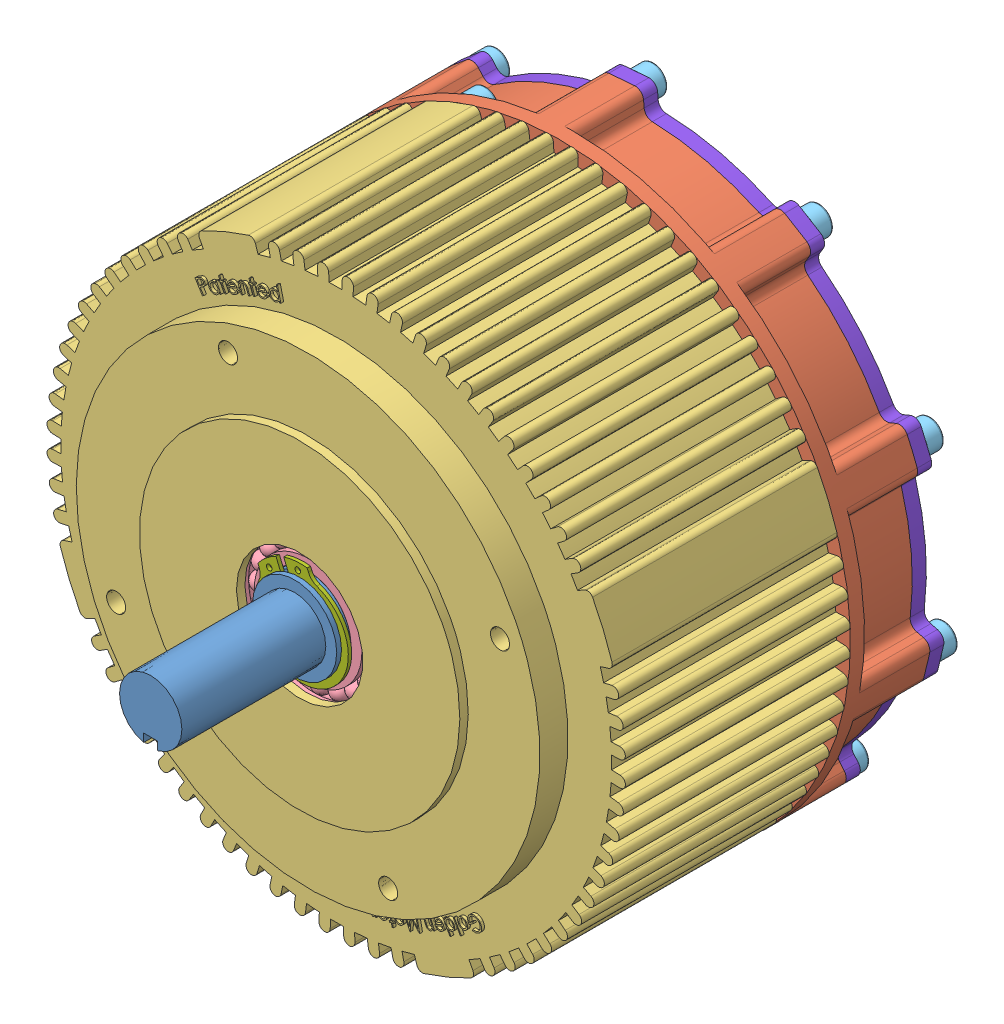
SolidWorks assembly (外形图）水冷图, configuration 默认. Lengths in mm.
Overall size (269.45 269.45 189).
25 component instances, 8 part files, 24 mates.
Components (placement in the parent):
- 普通轴-1: 普通轴 [默认] at (-1.1469 2.9597 -85) size (35 35 168.2)
- 水冷盖-1: 水冷盖 [默认] at (-1.1469 2.9597 -43.6) x (0 0 -1) z (0.922836 0.385193 0) size (49.2 206 206)
- 机壳-1: 机壳 [默认] at (-1.1469 2.9597 30.2) x (0.922836 0.385193 0) z (0 0 -1) size (206 206 93)
- Deep groove ball bearings GB-1: Deep groove ball bearings GB [Rolling bearings 16006 GB 276-94] at (-1.1469 2.9597 22.7) x (0 0 1) z (-0.99974 -0.022781 0) size (9 55 55)
- Hexagon socket head cap screws GB-2: Hexagon socket head cap screws GB [GB_FASTENER_SCREWS_HSHCS M6X16-N] at (-96.501 25.5783 -103.8) x (0 0 1) z (-1 0 0) size (22 10 10)
- Hexagon socket head cap screws GB-3: Hexagon socket head cap screws GB [GB_FASTENER_SCREWS_HSHCS M8X16-N] at (-64.9357 -2.2351 -105.8) x (0 0 1) z (-1 0 0) size (24 13 13)
- Hexagon socket head cap screws GB-4: Hexagon socket head cap screws GB [GB_FASTENER_SCREWS_HSHCS M4X12-N] at (31.032 -9.4809 7.2) x (0 0 1) z (-1 0 0) size (16 7 7)
- Hexagon socket head cap screws GB-8: Hexagon socket head cap screws GB [GB_FASTENER_SCREWS_HSHCS M6X16-N] at (-38.8958 93.3977 -73.8) x (0 0 1) z (-1 0 0) size (22 10 10)
- Hexagon socket head cap screws GB-9: Hexagon socket head cap screws GB [GB_FASTENER_SCREWS_HSHCS M6X16-N] at (36.602 -87.4782 -73.8) x (0 0 1) z (1 0 0) size (22 10 10)
- Deep groove ball bearings GB-2: Deep groove ball bearings GB [Rolling bearings 6304 GB 276-94] at (-1.1469 2.9597 -53.1) x (0 0 -1) z (0.923728 0.383049 0) size (15 52 52)
- Circlips for holes--Type A GB-1: Circlips for holes--Type A GB [GB_CONNECTING_PIECE_RING_RRH 52] at (-0.6872 1.8513 -62.8) x (0.923728 0.383049 0) z (0 0 -1) size (56.2 54.06 2)
- Circlips for shaft--Type B GB-1: Circlips for shaft--Type B GB [GB_CONNECTING_PIECE_RINGS_CSB 30] at (-0.7907 2.1007 28.8) x (0.923728 0.383049 0) z (0 0 -1) size (33.5 36.62 1.2)
- 水冷盖板-1: 水冷盖板 [默认] at (-1.1469 2.9597 -97.8) x (0.9967 0.081168 0) z (0 0 1) size (198.8 206 5)
- Hexagon socket head cap screws GB-19: Hexagon socket head cap screws GB [GB_FASTENER_SCREWS_HSHCS M6X16-N] at (-91.5848 -34.7892 -103.8) x (0 0 1) z (-0.809017 -0.587785 0) size (22 10 10)
- Hexagon socket head cap screws GB-20: Hexagon socket head cap screws GB [GB_FASTENER_SCREWS_HSHCS M6X16-N] at (-52.1244 -80.7379 -103.8) x (0 0 1) z (-0.309017 -0.951057 0) size (22 10 10)
- Hexagon socket head cap screws GB-21: Hexagon socket head cap screws GB [GB_FASTENER_SCREWS_HSHCS M6X16-N] at (6.8076 -94.7169 -103.8) x (0 0 1) z (0.309017 -0.951057 0) size (22 10 10)
- Hexagon socket head cap screws GB-22: Hexagon socket head cap screws GB [GB_FASTENER_SCREWS_HSHCS M6X16-N] at (62.7013 -71.3868 -103.8) x (0 0 1) z (0.809017 -0.587785 0) size (22 10 10)
- Hexagon socket head cap screws GB-23: Hexagon socket head cap screws GB [GB_FASTENER_SCREWS_HSHCS M6X16-N] at (94.2072 -19.6588 -103.8) x (0 0 1) z (1 0 0) size (22 10 10)
- Hexagon socket head cap screws GB-24: Hexagon socket head cap screws GB [GB_FASTENER_SCREWS_HSHCS M6X16-N] at (89.291 40.7087 -103.8) x (0 0 1) z (0.809017 0.587785 0) size (22 10 10)
- Hexagon socket head cap screws GB-25: Hexagon socket head cap screws GB [GB_FASTENER_SCREWS_HSHCS M6X16-N] at (49.8307 86.6573 -103.8) x (0 0 1) z (0.309017 0.951057 0) size (22 10 10)
- Hexagon socket head cap screws GB-26: Hexagon socket head cap screws GB [GB_FASTENER_SCREWS_HSHCS M6X16-N] at (-9.1014 100.6364 -103.8) x (0 0 1) z (-0.309017 0.951057 0) size (22 10 10)
- Hexagon socket head cap screws GB-27: Hexagon socket head cap screws GB [GB_FASTENER_SCREWS_HSHCS M6X16-N] at (-64.9951 77.3062 -103.8) x (0 0 1) z (-0.809017 0.587785 0) size (22 10 10)
- Hexagon socket head cap screws GB-28: Hexagon socket head cap screws GB [GB_FASTENER_SCREWS_HSHCS M8X16-N] at (4.0479 -60.8291 -105.8) x (0 0 1) z (0 -1 0) size (24 13 13)
- Hexagon socket head cap screws GB-29: Hexagon socket head cap screws GB [GB_FASTENER_SCREWS_HSHCS M8X16-N] at (62.6419 8.1545 -105.8) x (0 0 1) z (1 0 0) size (24 13 13)
- Hexagon socket head cap screws GB-30: Hexagon socket head cap screws GB [GB_FASTENER_SCREWS_HSHCS M8X16-N] at (-6.3417 66.7486 -105.8) x (0 0 1) z (0 1 0) size (24 13 13)
Mates (geometry in assembly coordinates):
- 同心3: concentric aligned: circle of 普通轴-1; circle of 水冷盖-1
- 重合4: coincident aligned: plane of 普通轴-1 through (-1.1469 2.9597 -45.6) normal (0 0 -1); plane of 水冷盖-1 through (-11.1619 26.9535 -45.6) normal (0 0 -1)
- 同心9: concentric aligned: circle of 机壳-1; circle of Deep groove ball bearings GB-1
- 重合10: coincident anti-aligned: plane of 机壳-1 through (-1.1469 2.9597 27.2) normal (0 0 -1); plane of Deep groove ball bearings GB-1 through (-1.4886 17.9558 27.2) normal (0 0 1)
- 同心12: concentric anti-aligned: circle of 水冷盖-1; circle of 机壳-1
- 重合13: coincident anti-aligned: circle of 水冷盖-1; plane of 机壳-1 through (-1.1469 2.9597 -62.8) normal (0 0 -1)
- 同心13: concentric aligned: circle of 水冷盖-1; circle of 机壳-1
- 同心15: concentric anti-aligned: circle of 水冷盖-1; circle of Hexagon socket head cap screws GB-8
- 重合14: coincident anti-aligned: plane of 水冷盖-1 through (-19.521 99.2218 -67.8) normal (0 0 -1); circle of Hexagon socket head cap screws GB-8
- 重合18: coincident anti-aligned: plane of 水冷盖-1 through (-11.1619 26.9535 -45.6) normal (0 0 -1); plane of Deep groove ball bearings GB-2 through (-7.0203 17.1236 -45.6) normal (0 0 1)
- 同心16: concentric aligned: circle of 水冷盖-1; circle of Deep groove ball bearings GB-2
- 同心17: concentric aligned: circle of 水冷盖-1; circle of Circlips for holes--Type A GB-1
- 重合19: coincident anti-aligned: plane of 水冷盖-1 through (-11.7397 28.3377 -60.8) normal (0 0 -1); plane of Circlips for holes--Type A GB-1 through (-0.6872 1.8513 -60.8) normal (0 0 1)
- 同心22: concentric anti-aligned: circle of 水冷盖-1; circle of 水冷盖板-1
- 同心23: concentric anti-aligned: circle of 水冷盖-1; circle of 水冷盖板-1
- 重合22: coincident anti-aligned: plane of 水冷盖-1 through (-40.8218 98.0118 -92.8) normal (0 0 -1); plane of 水冷盖板-1 through (-4.7704 102.8941 -92.8) normal (0 0 1)
- 同心24: concentric aligned: circle of Hexagon socket head cap screws GB-2; circle of 水冷盖板-1
- 重合23: coincident anti-aligned: circle of Hexagon socket head cap screws GB-2; plane of 水冷盖板-1 through (-4.7704 102.8941 -97.8) normal (0 0 -1)
- 同心25: concentric aligned: circle of Hexagon socket head cap screws GB-3; circle of 水冷盖板-1
- 重合24: coincident anti-aligned: circle of Hexagon socket head cap screws GB-3; plane of 水冷盖板-1 through (-4.7704 102.8941 -97.8) normal (0 0 -1)
- 同心26: concentric aligned: circle of 普通轴-1; circle of Circlips for shaft--Type B GB-1
- 重合25: coincident anti-aligned: plane of 普通轴-1 through (-1.1469 2.9597 28.8) normal (0 0 1); plane of Circlips for shaft--Type B GB-1 through (-0.7907 2.1007 28.8) normal (0 0 -1)
- 局部圆周阵列6: unknown: line of 水冷盖板-1 through (-1.1469 2.9597 -97.8) axis (0 0 1)
- 局部圆周阵列7: unknown: line of 水冷盖板-1 through (-1.1469 2.9597 -97.8) axis (0 0 1)
